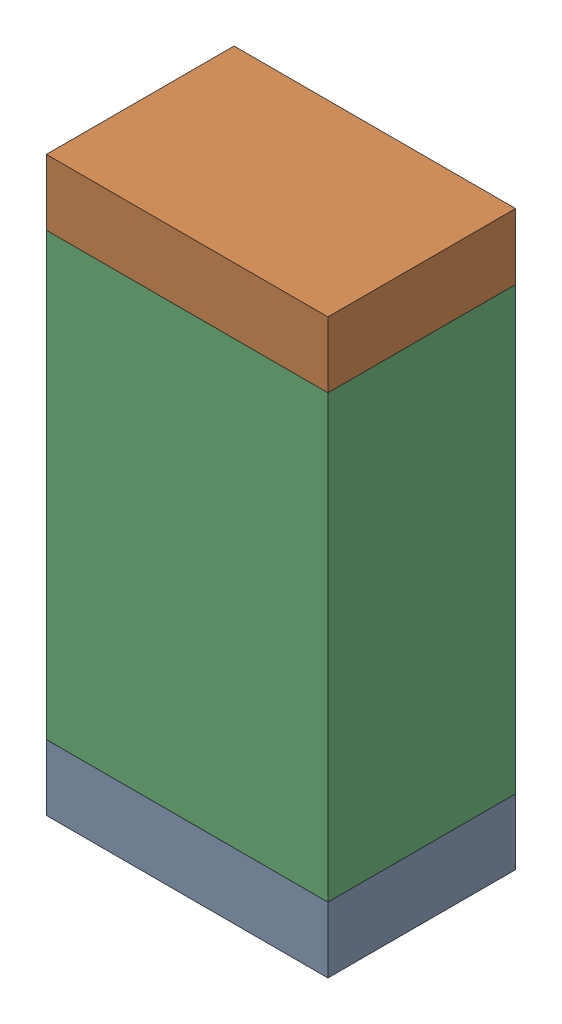
SolidWorks assembly R6, configuration Default. Lengths in mm.
Overall size (0.76 1.55 0.51).
6 component instances, 2 part files, 0 mates.
Components (placement in the parent):
- 822501776-1: 822501776 [Default] at (21.3867 4.7245 0) size (0.76 0.18 0.51)
  - Extruded_3-1: Extruded_3 [Default] at origin size (0.76 0.18 0.51)
- 822501776-2: 822501776 [Default] at (21.3867 6.0961 0) size (0.76 0.18 0.51)
  - Extruded_3-1: Extruded_3 [Default] at origin size (0.76 0.18 0.51)
- 822501912-1: 822501912 [Default] at (21.3867 5.4103 0) size (0.76 1.19 0.51)
  - Extruded_4-1: Extruded_4 [Default] at origin size (0.76 1.19 0.51)
